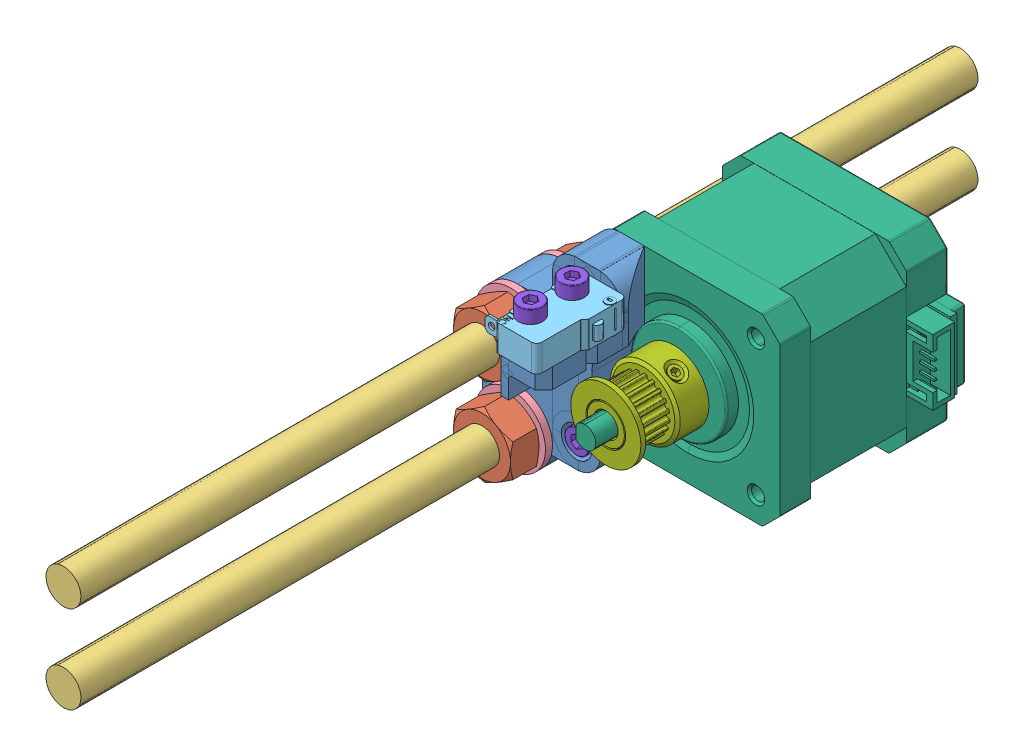
SolidWorks assembly Assembly y-axis back side, configuration Valor predeterminado. Lengths in mm.
Overall size (67.29 52.15 205).
18 component instances, 8 part files, 45 mates.
Components (placement in the parent):
- y-motor-1: y-motor [Valor predeterminado] at (0 -2 -11.25) size (32 48 28)
- Nut DIN 934 - M8-1: Nut DIN 934 - M8 [Valor predeterminado] at (0 8 -16.1) x (0 0 -1) z (0.866025 0.5 0) size (6.5 13 15.01)
- Threaded Rod DIN 975 - M8 x 205-1: Threaded Rod DIN 975 - M8 x 205 [Valor predeterminado] at (0 8 0) x (-0.43589 -0.9 0) z (0 0 1) size (8 8 205)
- Washer DIN 125A - M8-1: Washer DIN 125A - M8 [Valor predeterminado] at (0 8 -11.25) x (0 0 -1) z (0.452123 0.891955 0) size (1.6 16 16)
- Washer DIN 125A - M8-2: Washer DIN 125A - M8 [Valor predeterminado] at (0 28 0.35) x (0 0 -1) z (0.28551 0.958376 0) size (1.6 16 16)
- Washer DIN 125A - M8-3: Washer DIN 125A - M8 [Valor predeterminado] at (0 28 -11.25) x (0 0 -1) z (0.655489 0.755205 0) size (1.6 16 16)
- Washer DIN 125A - M8-4: Washer DIN 125A - M8 [Valor predeterminado] at (0 8 0.35) x (0 0 -1) z (0.269977 0.962867 0) size (1.6 16 16)
- Nut DIN 934 - M8-2: Nut DIN 934 - M8 [Valor predeterminado] at (0 8 3.6) x (0 0 -1) z (0.866025 0.5 0) size (6.5 13 15.01)
- Nut DIN 934 - M8-3: Nut DIN 934 - M8 [Valor predeterminado] at (0 28 -16.1) x (0 0 -1) z (0 1 0) size (6.5 13 15.01)
- Nut DIN 934 - M8-4: Nut DIN 934 - M8 [Valor predeterminado] at (0 28 3.6) x (0 0 -1) z (0.866025 0.5 0) size (6.5 13 15.01)
- Threaded Rod DIN 975 - M8 x 205-2: Threaded Rod DIN 975 - M8 x 205 [Valor predeterminado] at (0 28 0) x (0.997367 0.072523 0) z (0 0 1) size (8 8 205)
- Microswitch without leaver - KW11-3Z 5A 250VAC-1: Microswitch without leaver - KW11-3Z 5A 250VAC [Valor predeterminado] at (20.2125 43.2 8.8375) x (0 0 1) z (0 1 0) size (19.85 15.2 6.4)
- Stepper motor Nema 17-1: Stepper motor Nema 17 [Valor predeterminado] at (24.7456 51.1278 -23.75) x (0 0 -1) z (1 0 0) size (62.01 42.01 48.01)
- Pulley GT2 20T-1: Pulley GT2 20T [Valor predeterminado] at (29 27 -8.45) x (0 0 1) z (-0.851858 0.523772 0) size (16 16 16)
- Screw DIN 912 - M3 x 12 --- 12N-1: Screw DIN 912 - M3 x 12 --- 12N [Valor predeterminado] at (18 49.4 13.775) x (0 1 0) z (-0.900551 0 0.434751) size (15 5.5 5.5)
- Screw DIN 912 - M3 x 12 --- 12N-2: Screw DIN 912 - M3 x 12 --- 12N [Valor predeterminado] at (18 49.4 4.25) x (0 1 0) z (-0.88768 0 0.460461) size (15 5.5 5.5)
- Screw DIN 912 - M3 x 12 --- 12N-3: Screw DIN 912 - M3 x 12 --- 12N [Valor predeterminado] at (13.5 42.5 -1.25) x (0 0 1) z (0.896632 0.442776 0) size (15 5.5 5.5)
- Screw DIN 912 - M3 x 12 --- 12N-4: Screw DIN 912 - M3 x 12 --- 12N [Valor predeterminado] at (13.5 11.5 -1.25) x (0 0 1) z (0.896632 0.442776 0) size (15 5.5 5.5)
Mates (geometry in assembly coordinates):
- Concêntrico1: concentric: cylinder of assembly; cylinder of assembly; cylinder of y-motor-1 through (0 8 -12.25) axis (0 0 1) radius 4.1; cylinder of Washer DIN 125A - M8-1 through (0 8 -12.85) axis (0 0 1) radius 4.2
- Coincidente1: coincident: plane of assembly; plane of assembly; plane of y-motor-1 through (0 8 -11.25) normal (0 0 -1); plane of Washer DIN 125A - M8-1 through (0 8 -11.25) normal (0 0 1)
- Concêntrico2: concentric: cylinder of assembly; cylinder of assembly; cylinder of y-motor-1 through (0 8 -12.25) axis (0 0 1) radius 4.1; cylinder of Nut DIN 934 - M8-1 through (0 8 -19.35) axis (0 0 1) radius 3.4
- Coincidente2: coincident: plane of assembly; plane of assembly; plane of Nut DIN 934 - M8-1 through (-6.5 4.2472 -12.85) normal (0 0 1); plane of Washer DIN 125A - M8-1 through (0 8 -12.85) normal (0 0 -1)
- Paralelo1: parallel: plane of assembly; plane of assembly; plane of y-motor-1 through (-8 8 -11.25) normal (-1 0 0); plane of Nut DIN 934 - M8-1 through (-6.5 4.2472 -19.35) normal (-1 0 0)
- Concêntrico4: concentric: cylinder of assembly; cylinder of assembly; cylinder of y-motor-1 through (0 8 -12.25) axis (0 0 1) radius 4.1; cylinder of Washer DIN 125A - M8-4 through (0 8 -1.25) axis (0 0 1) radius 4.2
- Coincidente4: coincident: plane of assembly; plane of assembly; plane of y-motor-1 through (0 8 -1.25) normal (0 0 1); plane of Washer DIN 125A - M8-4 through (0 8 -1.25) normal (0 0 -1)
- Concêntrico5: concentric: cylinder of assembly; cylinder of assembly; cylinder of y-motor-1 through (0 28 -12.25) axis (0 0 1) radius 4.1; cylinder of Washer DIN 125A - M8-3 through (0 28 -12.85) axis (0 0 1) radius 4.2
- Coincidente5: coincident: plane of assembly; plane of assembly; plane of y-motor-1 through (-8 8 -11.25) normal (0 0 -1); plane of Washer DIN 125A - M8-3 through (0 28 -11.25) normal (0 0 1)
- Concêntrico6: concentric: cylinder of assembly; cylinder of assembly; cylinder of y-motor-1 through (0 28 -12.25) axis (0 0 1) radius 4.1; cylinder of Washer DIN 125A - M8-2 through (0 28 -1.25) axis (0 0 1) radius 4.2
- Coincidente6: coincident: plane of assembly; plane of assembly; plane of y-motor-1 through (-8 8 -1.25) normal (0 0 1); plane of Washer DIN 125A - M8-2 through (0 28 -1.25) normal (0 0 -1)
- Concêntrico7: concentric: cylinder of assembly; cylinder of assembly; cylinder of y-motor-1 through (0 28 -12.25) axis (0 0 1) radius 4.1; cylinder of Nut DIN 934 - M8-3 through (0 28 -19.35) axis (0 0 1) radius 3.4
- Coincidente7: coincident: plane of assembly; plane of assembly; plane of Washer DIN 125A - M8-3 through (0 28 -12.85) normal (0 0 -1); plane of Nut DIN 934 - M8-3 through (0 20.4944 -12.85) normal (0 0 1)
- Paralelo2: parallel: plane of assembly; plane of assembly; plane of y-motor-1 through (-8 8 -11.25) normal (-1 0 0); plane of Nut DIN 934 - M8-3 through (-6.5 24.2472 -19.35) normal (-1 0 0)
- Concêntrico9: concentric: cylinder of assembly; cylinder of assembly; cylinder of y-motor-1 through (0 28 -12.25) axis (0 0 1) radius 4.1; cylinder of Nut DIN 934 - M8-4 through (0 28 0.35) axis (0 0 1) radius 3.4
- Coincidente9: coincident: plane of assembly; plane of assembly; plane of Washer DIN 125A - M8-2 through (0 28 0.35) normal (0 0 1); plane of Nut DIN 934 - M8-4 through (-6.5 24.2472 0.35) normal (0 0 -1)
- Paralelo3: parallel: plane of assembly; plane of assembly; plane of y-motor-1 through (-8 8 -11.25) normal (-1 0 0); plane of Nut DIN 934 - M8-4 through (-6.5 24.2472 0.35) normal (-1 0 0)
- Concêntrico10: concentric: cylinder of assembly; cylinder of assembly; cylinder of y-motor-1 through (0 8 -12.25) axis (0 0 1) radius 4.1; cylinder of Nut DIN 934 - M8-2 through (0 8 0.35) axis (0 0 1) radius 3.4
- Coincidente11: coincident: plane of assembly; plane of assembly; plane of Washer DIN 125A - M8-4 through (0 8 0.35) normal (0 0 1); plane of Nut DIN 934 - M8-2 through (-6.5 4.2472 0.35) normal (0 0 -1)
- Paralelo4: parallel: plane of assembly; plane of assembly; plane of y-motor-1 through (-8 8 -11.25) normal (-1 0 0); plane of Nut DIN 934 - M8-2 through (-6.5 4.2472 0.35) normal (-1 0 0)
- Concêntrico11: concentric: cylinder of assembly; cylinder of assembly; cylinder of y-motor-1 through (0 8 -12.25) axis (0 0 1) radius 4.1; cylinder of Threaded Rod DIN 975 - M8 x 205-1 through (0 8 102.5) axis (0 0 -1) radius 4
- Concêntrico12: concentric: cylinder of assembly; cylinder of assembly; cylinder of y-motor-1 through (0 28 -12.25) axis (0 0 1) radius 4.1; cylinder of Threaded Rod DIN 975 - M8 x 205-2 through (0 28 102.5) axis (0 0 -1) radius 4
- Coincidente13: coincident: plane of assembly; plane of assembly; plane of Threaded Rod DIN 975 - M8 x 205-1 through (0 8 102.5) normal (0 0 1); plane of Threaded Rod DIN 975 - M8 x 205-2 through (0 28 102.5) normal (0 0 1)
- Coincidente14: coincident: plane of assembly; plane of assembly; plane of y-motor-1 through (14 40 -11.25) normal (0 1 0); plane of Microswitch without leaver - KW11-3Z 5A 250VAC-1 through (16.8604 40 4.25) normal (0 -1 0)
- Concêntrico13: concentric: cylinder of assembly; cylinder of assembly; cylinder of y-motor-1 through (18 43 4.25) axis (0 -1 0) radius 1.2; cylinder of Microswitch without leaver - KW11-3Z 5A 250VAC-1 through (18 46.4 4.25) axis (0 -1 0) radius 1.175
- Paralelo5: parallel: plane of assembly; plane of assembly; plane of y-motor-1 through (24 35 -11.25) normal (1 0 0); plane of Microswitch without leaver - KW11-3Z 5A 250VAC-1 through (24.5625 43.2 18.9375) normal (1 0 0)
- Coincidente17: coincident: plane of assembly; plane of assembly; plane of y-motor-1 through (8 11.5 -11.25) normal (0 0 -1); plane of Stepper motor Nema 17-1 through (29 27 -11.25) normal (0 0 1)
- Concêntrico14: concentric: cylinder of assembly; cylinder of assembly; cylinder of y-motor-1 through (13.5 11.5 -12.25) axis (0 0 1) radius 1.8; cylinder of Stepper motor Nema 17-1 through (13.5 11.5 -14.75) axis (0 0 1) radius 1.5
- Paralelo6: parallel: plane of assembly; plane of assembly; plane of y-motor-1 through (-8 8 -11.25) normal (-1 0 0); plane of Stepper motor Nema 17-1 through (8 48 -40.15) normal (-1 0 0)
- Concêntrico15: concentric: cylinder of Stepper motor Nema 17-1 through (29 27 -15.65) axis (0 0 -1) radius 2.5; cylinder of ? through (29 27 -1.95) axis (0 0 1) radius 2.5
- Concêntrico17: concentric: cylinder of assembly; cylinder of assembly; cylinder of Microswitch without leaver - KW11-3Z 5A 250VAC-1 through (18 46.4 13.775) axis (0 -1 0) radius 1.175; cylinder of Screw DIN 912 - M3 x 12 --- 12N-1 through (18 49.4 13.775) axis (0 1 0) radius 1.5
- Coincidente20: coincident: plane of assembly; plane of assembly; plane of Microswitch without leaver - KW11-3Z 5A 250VAC-1 through (16.8604 46.4 13.775) normal (0 1 0); plane of Screw DIN 912 - M3 x 12 --- 12N-1 through (16.8044 46.4 11.2985) normal (0 -1 0)
- Concêntrico18: concentric: cylinder of assembly; cylinder of assembly; cylinder of Microswitch without leaver - KW11-3Z 5A 250VAC-1 through (18 46.4 4.25) axis (0 -1 0) radius 1.175; cylinder of Screw DIN 912 - M3 x 12 --- 12N-2 through (18 49.4 4.25) axis (0 1 0) radius 1.5
- Coincidente21: coincident: plane of assembly; plane of assembly; plane of Microswitch without leaver - KW11-3Z 5A 250VAC-1 through (16.8604 46.4 4.25) normal (0 1 0); plane of Screw DIN 912 - M3 x 12 --- 12N-2 through (16.7337 46.4 1.8089) normal (0 -1 0)
- Coincidente22: coincident: plane of assembly; plane of assembly; plane of y-motor-1 through (13.5 42.5 -4.25) normal (0 0 1); plane of Screw DIN 912 - M3 x 12 --- 12N-3 through (14.7176 40.0343 -4.25) normal (0 0 -1)
- Concêntrico19: concentric: cylinder of assembly; cylinder of assembly; cylinder of y-motor-1 through (13.5 42.5 -12.25) axis (0 0 1) radius 1.8; cylinder of Screw DIN 912 - M3 x 12 --- 12N-3 through (13.5 42.5 -1.25) axis (0 0 1) radius 1.5
- Coincidente23: coincident: plane of assembly; plane of assembly; plane of y-motor-1 through (13.5 11.5 -4.25) normal (0 0 1); plane of Screw DIN 912 - M3 x 12 --- 12N-4 through (14.7176 9.0343 -4.25) normal (0 0 -1)
- Concêntrico21: concentric: cylinder of assembly; cylinder of assembly; cylinder of y-motor-1 through (13.5 11.5 -12.25) axis (0 0 1) radius 1.8; cylinder of Screw DIN 912 - M3 x 12 --- 12N-4 through (13.5 11.5 -1.25) axis (0 0 1) radius 1.5
- Paralelo7: parallel: line of assembly; line of Threaded Rod DIN 975 - M8 x 205-2 through (0 28 102.5) axis (0 0 -1); plane of assembly
- Coincidente26: coincident: line of assembly; line of Threaded Rod DIN 975 - M8 x 205-2 through (0 28 102.5) axis (0 0 -1); plane of assembly
- Coincidente28: coincident: line of assembly; line of Threaded Rod DIN 975 - M8 x 205-1 through (0 8 102.5) axis (0 0 -1); plane of assembly
- Tangente1: tangent: cylinder of assembly; cylinder of y-motor-1 through (0 8 -11.25) axis (0 0 1) radius 8; plane of assembly
- Coincidente29: coincident: plane of assembly through (0 0 0) normal (0 0 1); plane of Threaded Rod DIN 975 - M8 x 205-1 through (0 8 0) normal (0 0 1); plane of assembly
- Distância1: distance = 5.75 mm: plane of assembly through (0 0 0) normal (0 0 1); plane of assembly; plane of y-motor-1 through (0 -2 5.75) normal (0 0 1)
- Distância3: distance = 3.25 mm: plane of assembly; plane of assembly; plane of Pulley GT2 20T-1 through (29 27 2.5) normal (0 0 1); plane of y-motor-1 through (0 -2 5.75) normal (0 0 1)
